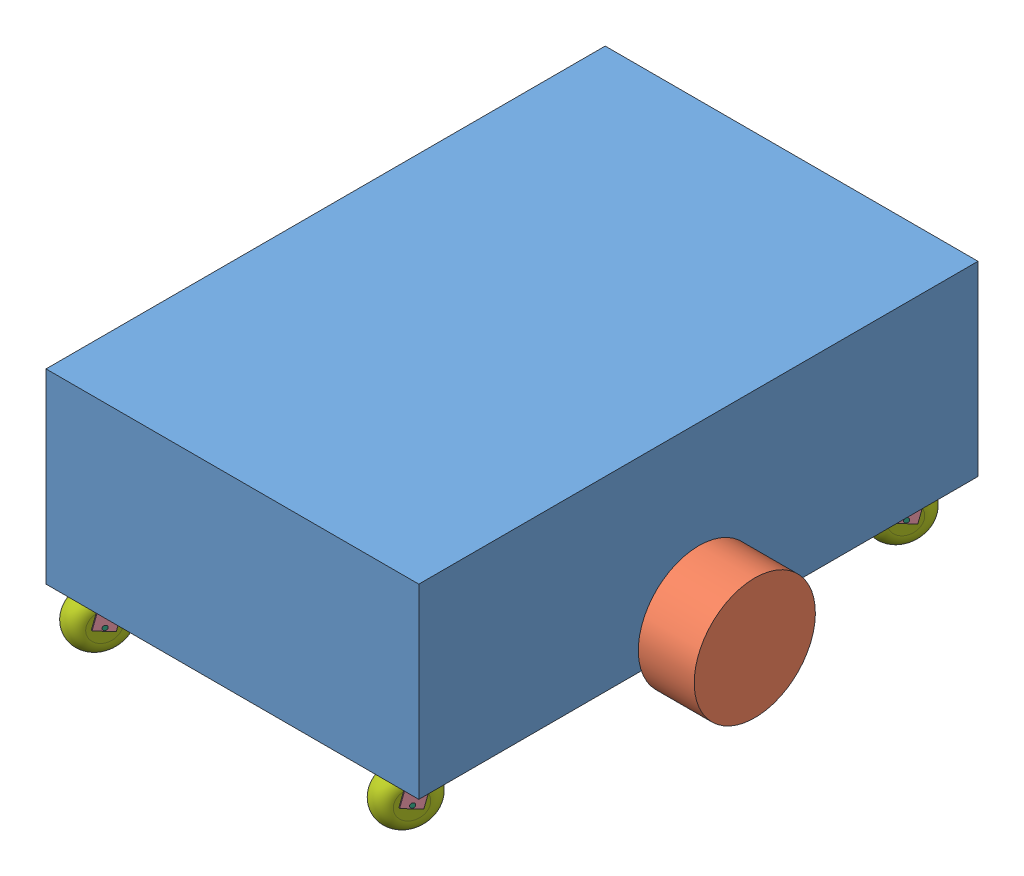
SolidWorks assembly Assem1, configuration Default. Lengths in mm.
Overall size (521 269.25 618.59).
23 component instances, 7 part files, 17 mates.
Components (placement in the parent):
- Frame-1: Frame [Default] at (-186.3224 -70.505 -327.2559) size (400 204 600)
- Wheel-1: Wheel [Default] at (-246.8224 -49.505 -27.2559) x (1 0 0) z (0 -0.549261 0.835651) size (85 130 130)
- Wheel-3: Wheel [Default] at (274.1776 -49.505 -27.2559) x (-1 0 0) z (0 0.559719 -0.828683) size (85 130 130)
- Revolute1-1: Revolute1 [Default] at (-151.3224 -45.505 -292.2559) x (-0.894732 0 -0.446603) z (-0.446603 0 0.894732) size (30 20 30)
- Revolute2-1: Revolute2 [Default] at (-147.6708 -63.8205 -299.5715) x (0.894732 0 0.446603) z (0.432339 -0.250717 -0.866155) size (35 51.33 20)
- Pin1-1: Pin1 [Default] at (-164.7434 -55.505 -298.955) x (0.446603 0 -0.894732) z (0.894732 0 0.446603) size (10 10 30)
- Pin2-1: Pin2 [Default] at (-140.4793 -97.1316 -274.7944) x (-0.446603 0 0.894732) z (-0.894732 0 -0.446603) size (5 5 35)
- Caster wheel-1: Caster wheel [Default] at (-141.8214 -97.1316 -275.4643) x (-0.22846 -0.859254 0.4577) z (-0.894732 0 -0.446603) size (60 60 30)
- Revolute2-5: Revolute2 [Default] at (-147.6708 -63.8205 230.4285) x (0.894732 0 0.446603) z (0.432339 -0.250717 -0.866155) size (35 51.33 20)
- Revolute2-6: Revolute2 [Default] at (182.3292 -63.8205 -299.5715) x (0.894732 0 0.446603) z (0.432339 -0.250717 -0.866155) size (35 51.33 20)
- Revolute2-7: Revolute2 [Default] at (182.3292 -63.8205 230.4285) x (0.894732 0 0.446603) z (0.432339 -0.250717 -0.866155) size (35 51.33 20)
- Pin2-5: Pin2 [Default] at (-140.4793 -97.1316 255.2056) x (-0.446603 0 0.894732) z (-0.894732 0 -0.446603) size (5 5 35)
- Pin2-6: Pin2 [Default] at (189.5207 -97.1316 -274.7944) x (-0.446603 0 0.894732) z (-0.894732 0 -0.446603) size (5 5 35)
- Pin2-7: Pin2 [Default] at (189.5207 -97.1316 255.2056) x (-0.446603 0 0.894732) z (-0.894732 0 -0.446603) size (5 5 35)
- Caster wheel-5: Caster wheel [Default] at (-141.8214 -97.1316 254.5357) x (-0.22846 -0.859254 0.4577) z (-0.894732 0 -0.446603) size (60 60 30)
- Caster wheel-6: Caster wheel [Default] at (188.1786 -97.1316 -275.4643) x (-0.22846 -0.859254 0.4577) z (-0.894732 0 -0.446603) size (60 60 30)
- Caster wheel-7: Caster wheel [Default] at (188.1786 -97.1316 254.5357) x (-0.22846 -0.859254 0.4577) z (-0.894732 0 -0.446603) size (60 60 30)
- Revolute1-5: Revolute1 [Default] at (-151.3224 -45.505 237.7441) x (-0.894732 0 -0.446603) z (-0.446603 0 0.894732) size (30 20 30)
- Revolute1-6: Revolute1 [Default] at (178.6776 -45.505 -292.2559) x (-0.894732 0 -0.446603) z (-0.446603 0 0.894732) size (30 20 30)
- Revolute1-7: Revolute1 [Default] at (178.6776 -45.505 237.7441) x (-0.894732 0 -0.446603) z (-0.446603 0 0.894732) size (30 20 30)
- Pin1-5: Pin1 [Default] at (-164.7434 -55.505 231.045) x (0.446603 0 -0.894732) z (0.894732 0 0.446603) size (10 10 30)
- Pin1-6: Pin1 [Default] at (165.2566 -55.505 -298.955) x (0.446603 0 -0.894732) z (0.894732 0 0.446603) size (10 10 30)
- Pin1-7: Pin1 [Default] at (165.2566 -55.505 231.045) x (0.446603 0 -0.894732) z (0.894732 0 0.446603) size (10 10 30)
Mates (geometry in assembly coordinates):
- Concentric2: concentric anti-aligned: circle of Frame-1; circle of Wheel-1
- Concentric3: concentric anti-aligned: circle of Frame-1; circle of Wheel-3
- Concentric4: concentric anti-aligned: circle of Frame-1; circle of Revolute1-1
- Coincident9: coincident anti-aligned: circle of Frame-1; circle of Revolute1-1
- Concentric9: concentric aligned: cylinder of Revolute1-1 through (-137.9014 -55.505 -285.5569) axis (-0.894732 0 -0.446603) radius 5; cylinder of Revolute2-1 through (-135.6646 -55.505 -284.4404) axis (-0.894732 0 -0.446603) radius 5
- Concentric10: concentric aligned: cylinder of Revolute1-1 through (-137.9014 -55.505 -285.5569) axis (-0.894732 0 -0.446603) radius 5; cylinder of Pin1-1 through (-137.9014 -55.505 -285.5569) axis (-0.894732 0 -0.446603) radius 5
- Tangent5: tangent: curve of Revolute1-1; circle of Pin1-1
- Concentric11: concentric aligned: cylinder of Revolute2-1 through (-135.6646 -55.505 -284.4404) axis (-0.894732 0 -0.446603) radius 5; cylinder of Pin1-1 through (-137.9014 -55.505 -285.5569) axis (-0.894732 0 -0.446603) radius 5
- Coincident14: coincident anti-aligned: plane of Revolute1-1 through (-151.3338 -65.505 -309.0265) normal (0.894732 0 0.446603); plane of Revolute2-1 through (-161.2366 -43.3172 -289.1872) normal (-0.894732 0 -0.446603)
- Coincident15: coincident aligned: circle of Revolute2-1; circle of Pin2-1
- Concentric12: concentric aligned: circle of Revolute2-1; circle of Caster wheel-1
- Coincident17: coincident aligned: circle of Revolute2-1; circle of Caster wheel-1
- LimitAngle1: limit planar angle = 0.462965 rad aligned: plane of Revolute2-6 through (193.5081 -102.543 -282.783) normal (0.894732 0 0.446603); plane of Frame-1 through (213.6776 -70.505 272.7441) normal (1 0 0)
- LimitAngle3: limit planar angle = 1.317376 rad anti-aligned: plane of Revolute2-1 through (-176.4543 -97.5286 -281.091) normal (-0.432339 0.250717 0.866155); plane of Frame-1 through (-186.3224 -20.505 -327.2559) normal (0 -1 0)
- LimitAngle4: limit planar angle = 1.317376 rad anti-aligned: plane of Revolute2-1 through (-176.4543 -97.5286 -281.091) normal (-0.432339 0.250717 0.866155); plane of Frame-1 through (-186.3224 -20.505 -327.2559) normal (0 -1 0)
- Coincident21: coincident anti-aligned: circle of Frame-1; circle of Wheel-1
- Coincident22: coincident anti-aligned: circle of Frame-1; circle of Wheel-3
